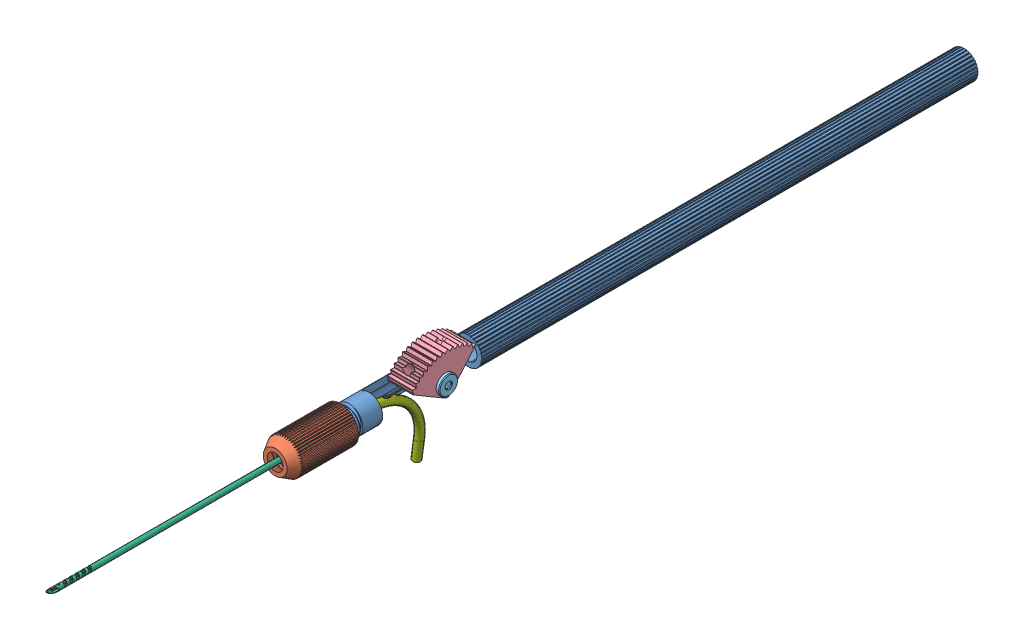
SolidWorks assembly Clinical Tool Assembly, configuration Default. Lengths in mm.
Overall size (12.73 38.39 230.72).
7 component instances, 7 part files, 9 mates.
Components (placement in the parent):
- Handle M7 threads-1: Handle M7 threads [91290A162] at (75.9426 89.8859 210.1647) size (8.08 7.4 171.29)
- 90591A154 M7 collet clamp-1: 90591A154 M7 collet clamp [90591A154] at (75.9426 89.8859 203.2216) x (-0.71098 -0.703212 0) z (0 0 1) size (9 9 17)
- collet-1: collet [Default] at (75.9426 89.8859 189.6173) x (-0.792711 0.609597 0) z (0 0 1) size (5.98 5.98 19)
- wedge v-5 14-Sep-2017_5mm_stainless steel-1: wedge v-5 14-Sep-2017_5mm_stainless steel [Default] at (77.1176 88.6113 182.6997) x (0 0.043667 0.999046) z (-1 0 0) size (31.24 27.17 6.35)
- 90318A101_ULTRA LOW PROFILE TYPE 316 SS SHOULDER SCREW-1: 90318A101_ULTRA LOW PROFILE TYPE 316 SS SHOULDER SCREW [90318A101] at (81.0863 89.8859 174.1647) x (0 0 -1) z (1 0 0) size (4.76 4.76 7.42)
- 135deg CCM V-1 Wrist left-1: 135deg CCM V-1 Wrist left [Default] at (75.9426 89.8859 258.7971) x (0 -1 0) z (0 0 1) size (1.25 1.49 71.09)
- laser suction exit tube-1: laser suction exit tube [Default] at (75.9426 89.8859 194.4658) x (0.990828 -0.135127 0) z (0 0 1) size (2 21 109.01)
Mates (geometry in assembly coordinates):
- Concentric1: concentric aligned: circle of Handle M7 threads-1; circle of collet-1
- Concentric2: concentric anti-aligned: circle of Handle M7 threads-1; circle of 90591A154 M7 collet clamp-1
- Concentric5: concentric aligned: circle of Handle M7 threads-1; circle of 135deg CCM V-1 Wrist left-1
- Concentric6: concentric aligned: circle of Handle M7 threads-1; circle of laser suction exit tube-1
- Coincident4: coincident anti-aligned: plane of Handle M7 threads-1 through (73.9426 89.8859 210.1647) normal (1 0 0); plane of wedge v-5 14-Sep-2017_5mm_stainless steel-1 through (73.9426 86.2189 173.5509) normal (-1 0 0)
- Concentric7: concentric anti-aligned: circle of Handle M7 threads-1; circle of wedge v-5 14-Sep-2017_5mm_stainless steel-1
- Coincident5: coincident anti-aligned: plane of wedge v-5 14-Sep-2017_5mm_stainless steel-1 through (80.2926 86.2189 173.5509) normal (1 0 0); plane of 90318A101_ULTRA LOW PROFILE TYPE 316 SS SHOULDER SCREW-1 through (80.2926 87.5046 174.1647) normal (-1 0 0)
- Concentric8: concentric aligned: circle of wedge v-5 14-Sep-2017_5mm_stainless steel-1; circle of 90318A101_ULTRA LOW PROFILE TYPE 316 SS SHOULDER SCREW-1
- Parallel1: parallel anti-aligned: plane of Handle M7 threads-1 through (75.9426 89.8859 210.1647) normal (0 1 0); plane of 135deg CCM V-1 Wrist left-1
